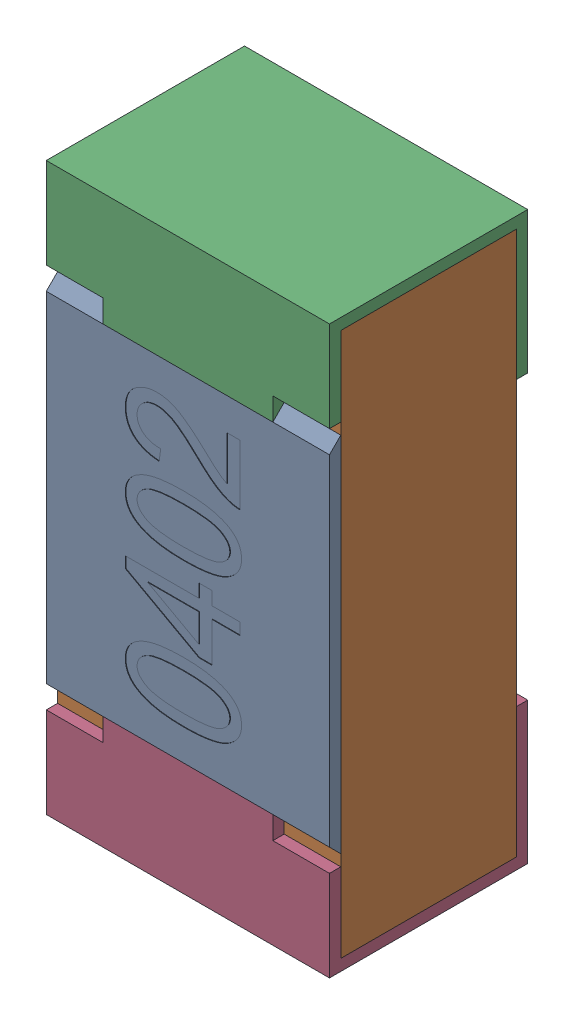
SolidWorks assembly R22, configuration Standard. Lengths in mm.
Overall size (0.5 1 0.35).
5 component instances, 4 part files, 0 mates.
Components (placement in the parent):
- R22-subassembly-1-1: R22-subassembly-1 [Standard] at (-15.5 -0.9999 0) x (0 1 0) z (0 0 1) size (1 0.5 0.35)
  - User Library-R_0402-1: User Library-R_0402 [Standard] at origin size (0.64 0.5 0.02)
  - User Library-R_0402-1-1: User Library-R_0402-1 [Standard] at origin size (0.96 0.5 0.31)
  - User Library-R_0402-2-1: User Library-R_0402-2 [Standard] at origin size (0.25 0.5 0.35)
  - User Library-R_0402-3-1: User Library-R_0402-3 [Standard] at origin size (0.25 0.5 0.35)
